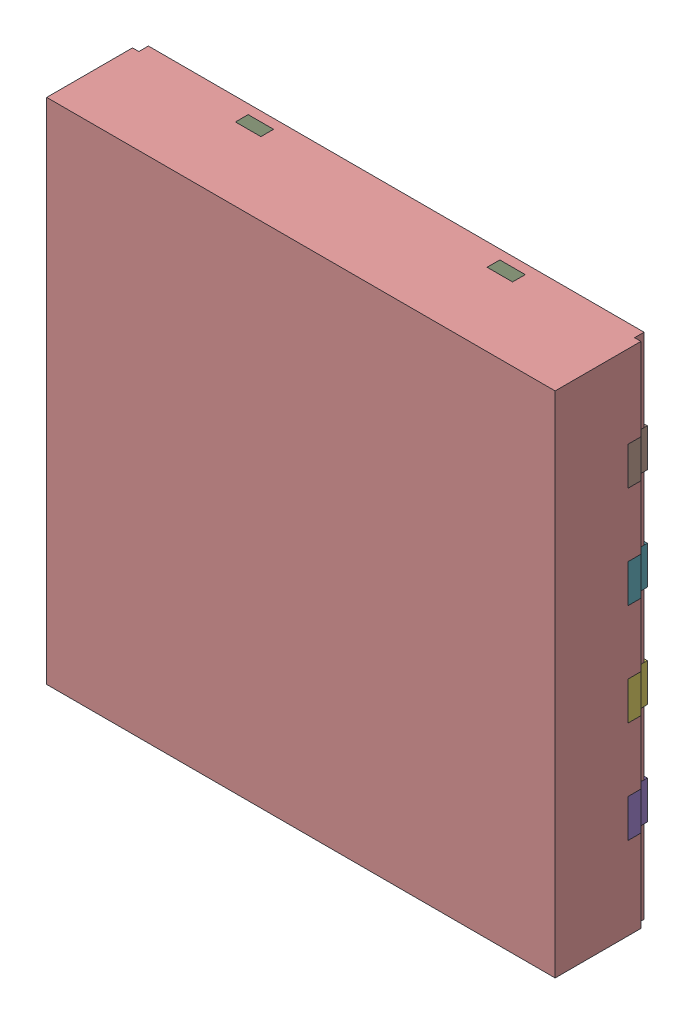
SolidWorks assembly IC2, configuration По умолчанию. Lengths in mm.
Overall size (4 4 0.78).
12 component instances, 10 part files, 0 mates.
Components (placement in the parent):
- NGU0008C_ASM-1: NGU0008C_ASM [По умолчанию] at origin size (4 4 0.78)
  - FRAME-NGU0008C_AF0-1: FRAME-NGU0008C_AF0 [По умолчанию] x (1 0 0) z (0 -1 0) size (4 0.2 4)
    - FRAME-NGU0008C_AF0-Part-1-1: FRAME-NGU0008C_AF0-Part-1 [По умолчанию] at origin size (0.4 0.2 0.3)
    - FRAME-NGU0008C_AF0-Part-2-1: FRAME-NGU0008C_AF0-Part-2 [По умолчанию] at origin size (0.4 0.2 0.3)
    - FRAME-NGU0008C_AF0-Part-3-1: FRAME-NGU0008C_AF0-Part-3 [По умолчанию] at origin size (0.4 0.2 0.3)
    - FRAME-NGU0008C_AF0-Part-4-1: FRAME-NGU0008C_AF0-Part-4 [По умолчанию] at origin size (0.4 0.2 0.3)
    - FRAME-NGU0008C_AF0-Part-5-1: FRAME-NGU0008C_AF0-Part-5 [По умолчанию] at origin size (0.4 0.2 0.3)
    - FRAME-NGU0008C_AF0-Part-6-1: FRAME-NGU0008C_AF0-Part-6 [По умолчанию] at origin size (0.4 0.2 0.3)
    - FRAME-NGU0008C_AF0-Part-7-1: FRAME-NGU0008C_AF0-Part-7 [По умолчанию] at origin size (0.4 0.2 0.3)
    - FRAME-NGU0008C_AF0-Part-8-1: FRAME-NGU0008C_AF0-Part-8 [По умолчанию] at origin size (0.4 0.2 0.3)
    - FRAME-NGU0008C_AF0-Part-9-1: FRAME-NGU0008C_AF0-Part-9 [По умолчанию] at origin size (2.18 0.2 4)
  - NGU0008C_ASM-Part-1-1: NGU0008C_ASM-Part-1 [По умолчанию] at (0 0 0.025) x (1 0 0) z (0 -1 0) size (4 0.75 4)
